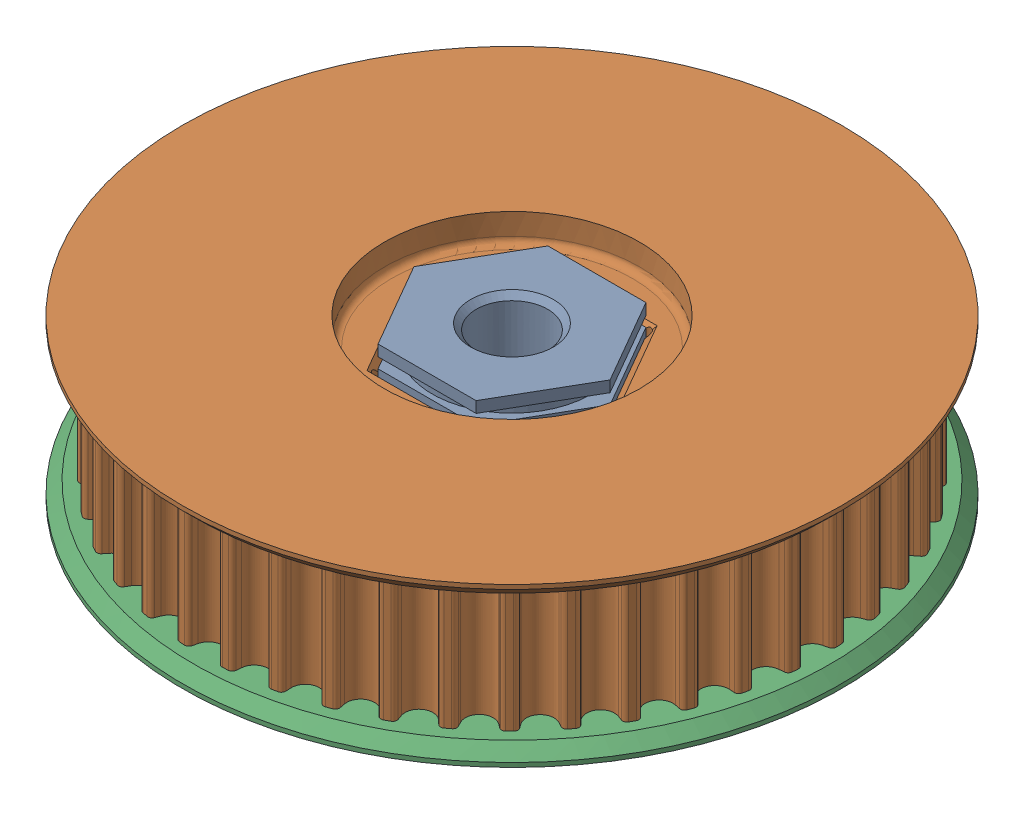
SolidWorks assembly 8MM_SHAFT_44T_HTD_PULLEY_ASM, configuration Default. Lengths in mm.
Overall size (100.97 27.3 100.97).
7 component instances, 5 part files, 0 mates.
Components (placement in the parent):
- 8MM_PULLEY_HUB-1: 8MM_PULLEY_HUB [Default] at origin size (22 26.54 19.05)
- HTD_TB_PULLEY_44T-1: HTD_TB_PULLEY_44T [Default] at (0 25.555 0) x (-1 0 0) z (0 -1 0) size (73.91 73.91 16.02)
- 44T_HTD_PULLEY_FLANGE-1: 44T_HTD_PULLEY_FLANGE [Default] at (0 9.5302 0) x (0.5 0 0.866025) z (-0.866025 0 0.5) size (73.91 1.75 73.91)
- 217-2736_20121205_ASM-1: 217-2736_20121205_ASM [Default] at (-4.5154 5.7531 -2.6156) x (-1 0 0) z (0 1 0) size (25.39 25.4 6.35)
  - 217-2736_20121205_1_ASM-1: 217-2736_20121205_1_ASM [Default] at origin size (25.39 25.4 6.35)
    - 217-2736-001_REV1-1-SOLID1-1: 217-2736-001_REV1-1-SOLID1 [Default] at origin size (25.39 25.4 6.35)
    - 92185A108-1-SOLID1-1: 92185A108-1-SOLID1 [Default] at origin size (4.65 12.51 4.65)
